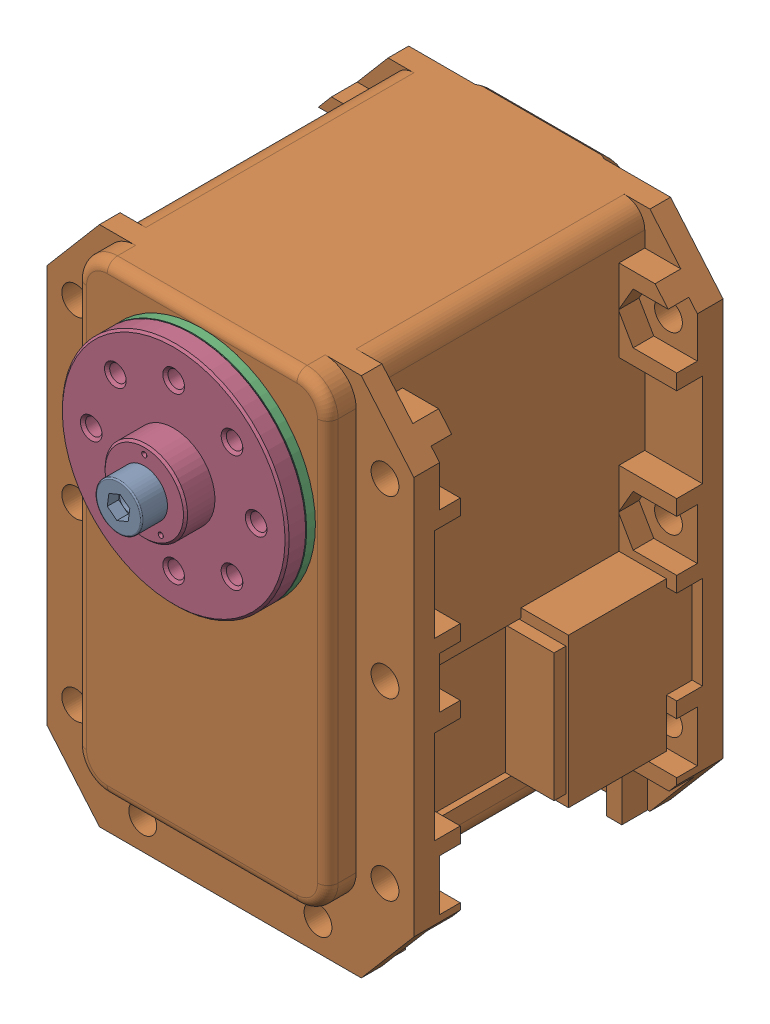
SolidWorks assembly MX-28(T)-7, configuration Default. Lengths in mm.
Overall size (35.6 54.13 45.1).
4 component instances, 4 part files, 0 mates.
Components (placement in the parent):
- WB_M2.5x8-1: WB_M2.5x8 [Default] at (0 0 25.85) x (0 0 -1) z (-0.991137 0.132843 0) size (10.5 4.5 4.5)
- dynamixel_x28series(Défaut)-1: dynamixel_x28series(Défaut) [Default] at origin size (35.6 50.71 41.85)
- trust_washer(Défaut)-1: trust_washer(Défaut) [Default] at (0 0 18.6) x (-0.666375 -0.745617 0) z (0.745617 -0.666375 0) size (22 0.85 22)
- HN07-N101(Défaut)-1: HN07-N101(Défaut) [Default] at (0 0 18.5) x (1 0 0) z (0 -1 0) size (22 5.85 22)
